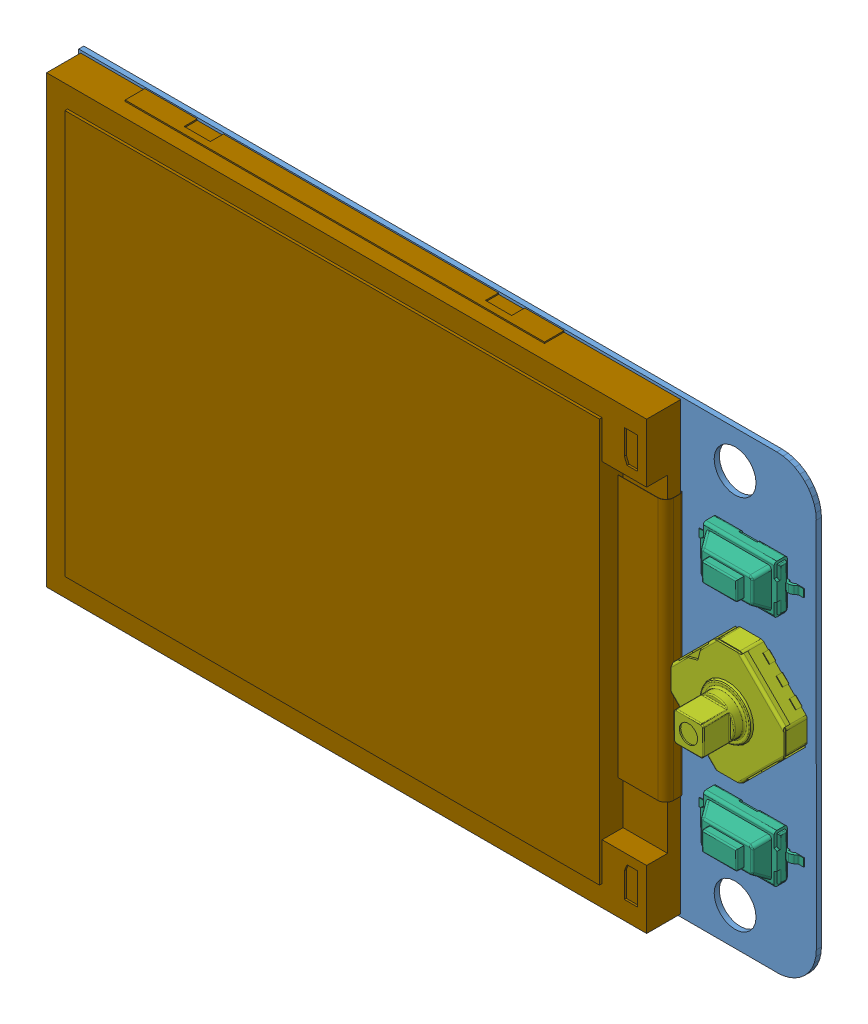
SolidWorks assembly 1.8-TFT-128x160, configuration Default. Lengths in mm.
Overall size (56.69 34.42 11.6).
25 component instances, 9 part files, 0 mates.
Components (placement in the parent):
- Board1.8-TFT-128_160-1: Board1.8-TFT-128_160 [默认] at (0 0 -0.3912) size (56.3 34.42 0.39)
- C11.8-TFT-128_160-1: C11.8-TFT-128_160 [默认] at origin size (0.8 1.6 0.6)
  - CAP-0603-1: CAP-0603 [默认] at (3.5258 -10.6299 -0.3912) x (0 1 0) z (0 0 -1) size (1.6 0.8 0.6)
- C21.8-TFT-128_160-1: C21.8-TFT-128_160 [默认] at origin size (0.8 1.6 0.6)
  - CAP-0603-1: CAP-0603 [默认] at (11.4252 -10.6299 -0.3912) x (0 1 0) z (0 0 -1) size (1.6 0.8 0.6)
- C31.8-TFT-128_160-1: C31.8-TFT-128_160 [默认] at origin size (0.8 1.6 0.6)
  - CAP-0603-1: CAP-0603 [默认] at (13.4318 -10.6299 -0.3912) x (0 1 0) z (0 0 -1) size (1.6 0.8 0.6)
- CN11.8-TFT-128_160-1: CN11.8-TFT-128_160 [默认] at origin size (6.5 13.95 6.5)
  - Pin-Header-2.00-Straight_SMD-14-1: Pin-Header-2.00-Straight_SMD-14 [默认] at (-0.5853 -0.0607 -0.7912) x (0 1 0) z (1 0 0) size (13.95 6.5 6.5)
- Q11.8-TFT-128_160-1: Q11.8-TFT-128_160 [默认] at origin size (3 3.01 1.3)
  - SOT323-3-1: SOT323-3 [默认] at (18.9992 -1.8303 -0.3912) x (0 1 0) z (-1 0 0) size (3.01 1.3 3)
- R11.8-TFT-128_160-1: R11.8-TFT-128_160 [默认] at origin size (1.6 0.8 0.46)
  - RES-0603-1: RES-0603 [默认] at (18.4531 0.8381 -0.6312) x (0 -1 0) z (1 0 0) size (0.8 0.46 1.6)
- R21.8-TFT-128_160-1: R21.8-TFT-128_160 [默认] at origin size (1.6 0.8 0.46)
  - RES-0603-1: RES-0603 [默认] at (18.453 2.6671 -0.6312) x (0 1 0) z (-1 0 0) size (0.8 0.46 1.6)
- Back1.8-TFT-128_160-1: Back1.8-TFT-128_160 [默认] at origin size (8 3.7 2.65)
  - Switch-PB-1: Switch-PB [默认] at (40.789 8.932 0) x (1 0 0) z (0 -1 0) size (8 2.65 3.7)
- Start1.8-TFT-128_160-1: Start1.8-TFT-128_160 [默认] at origin size (8 3.7 2.65)
  - Switch-PB-1: Switch-PB [默认] at (40.789 -8.868 0) x (1 0 0) z (0 -1 0) size (8 2.65 3.7)
- S31.8-TFT-128_160-1: S31.8-TFT-128_160 [默认] at origin size (10.68 10.68 5.26)
  - Switch-ALPS-5-1: Switch-ALPS-5 [默认] at (40.7625 -0.0045 1.65) x (0.707107 0.707107 0) z (0 0 -1) size (7.55 7.55 5.26)
- U11.8-TFT-128_160-1: U11.8-TFT-128_160 [默认] at origin size (2.8 2.9 1.45)
  - SOT23-5-1: SOT23-5 [默认] at (7.5414 -10.5665 -0.3912) x (0 1 0) z (0 0 -1) size (2.9 2.8 1.45)
- LCD1.8-TFT-128_160-1: LCD1.8-TFT-128_160 [默认] at origin size (46.13 34.2 2.9)
  - 1.8-TFT-1: 1.8-TFT [默认] at (35.3569 0.0001 0) x (0 1 0) z (0 0 1) size (34.2 46.13 2.9)
